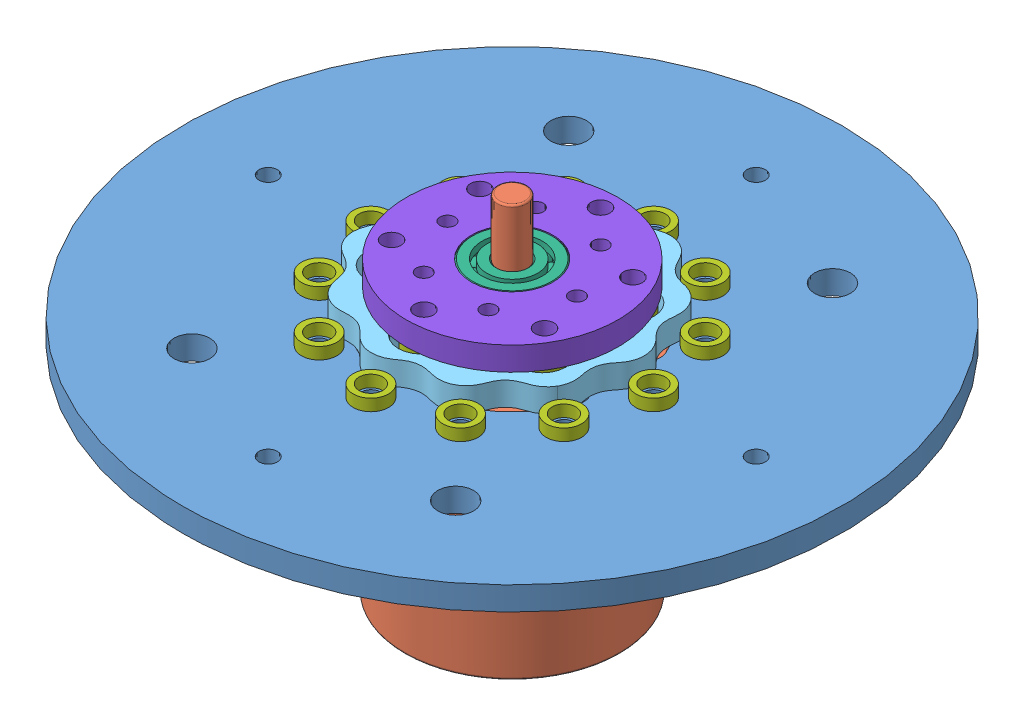
SolidWorks assembly Cycloidal Spindex Driver Assembly, configuration Default. Lengths in mm.
Overall size (177.8 93.26 177.8).
25 component instances, 8 part files, 20 mates.
Components (placement in the parent):
- Primary mounting-cooling plate-1: Primary mounting-cooling plate [Default] at (56.7267 81.535 113.5458) size (177.8 6.35 177.8)
- REV Neo Brushless-1: REV Neo Brushless [Default] at (56.7267 81.535 113.5458) x (1 0 0) z (0 1 0) size (60.81 60.02 93.26)
- Input from NEO-1: Input from NEO [Default] at (55.3519 87.885 112.7521) x (0.866043 0 0.49997) z (-0.49997 0 0.866043) size (12.7 6.35 12.7)
- 60355K505_Ball Bearing-1: 60355K505_Ball Bearing [60355K505] at (55.3519 91.06 112.7521) x (-0.255254 0 0.966874) z (0 -1 0) size (28.57 28.57 6.35)
- Cycloidal rotor-1: Cycloidal rotor [Default] at (55.3519 94.235 112.7521) x (-0.866026 0 -0.499999) z (0 -1 0) size (68.8 69.37 6.35)
- 5972K91_Ball Bearing-1: 5972K91_Ball Bearing [5972K91] at (56.7267 97.735 113.5458) x (-0.141937 0 0.989876) z (0 -1 0) size (22 22 7)
- Tiny bearing from thriftybot-2: Tiny bearing from thriftybot [Default] at (23.7311 87.885 94.4958) x (0.99755 0 -0.06995) z (0.06995 0 0.99755) size (9.53 3.17 9.53)
- Tiny bearing from thriftybot-3: Tiny bearing from thriftybot [Default] at (18.6267 87.885 113.5458) x (0.828929 0 -0.559354) z (0.559354 0 0.828929) size (9.53 3.17 9.53)
- Tiny bearing from thriftybot-4: Tiny bearing from thriftybot [Default] at (23.7311 87.885 132.5958) x (0.438196 0 -0.898879) z (0.898879 0 0.438196) size (9.53 3.17 9.53)
- Tiny bearing from thriftybot-5: Tiny bearing from thriftybot [Default] at (37.6767 87.885 146.5413) x (-0.06995 0 -0.99755) z (0.99755 0 -0.06995) size (9.53 3.17 9.53)
- Tiny bearing from thriftybot-6: Tiny bearing from thriftybot [Default] at (56.7267 87.885 151.6458) x (-0.559354 0 -0.828929) z (0.828929 0 -0.559354) size (9.53 3.17 9.53)
- Tiny bearing from thriftybot-7: Tiny bearing from thriftybot [Default] at (75.7767 87.885 146.5413) x (-0.898879 0 -0.438196) z (0.438196 0 -0.898879) size (9.53 3.17 9.53)
- Tiny bearing from thriftybot-8: Tiny bearing from thriftybot [Default] at (89.7223 87.885 132.5958) x (-0.99755 0 0.06995) z (-0.06995 0 -0.99755) size (9.53 3.17 9.53)
- Tiny bearing from thriftybot-9: Tiny bearing from thriftybot [Default] at (94.8267 87.885 113.5458) x (-0.828929 0 0.559354) z (-0.559354 0 -0.828929) size (9.53 3.17 9.53)
- Tiny bearing from thriftybot-10: Tiny bearing from thriftybot [Default] at (89.7223 87.885 94.4958) x (-0.438196 0 0.898879) z (-0.898879 0 -0.438196) size (9.53 3.17 9.53)
- Tiny bearing from thriftybot-11: Tiny bearing from thriftybot [Default] at (75.7767 87.885 80.5502) x (0.06995 0 0.99755) z (-0.99755 0 0.06995) size (9.53 3.17 9.53)
- Tiny bearing from thriftybot-12: Tiny bearing from thriftybot [Default] at (56.7267 87.885 75.4458) x (0.559354 0 0.828929) z (-0.828929 0 0.559354) size (9.53 3.17 9.53)
- Tiny bearing from thriftybot-13: Tiny bearing from thriftybot [Default] at (37.6767 87.885 80.5502) x (0.898879 0 0.438196) z (-0.438196 0 0.898879) size (9.53 3.17 9.53)
- Output disk-1: Output disk [Default] at (56.7267 94.885 113.5458) x (1 0 -0.000001) z (0.000001 0 1) size (57.15 6.35 57.15)
- Tiny bearing from thriftybot-14: Tiny bearing from thriftybot [Default] at (36.1045 91.71 125.452) x (0.999928 0 -0.011986) z (0.011986 0 0.999928) size (9.53 3.17 9.53)
- Tiny bearing from thriftybot-15: Tiny bearing from thriftybot [Default] at (56.7267 91.71 137.3583) x (0.489584 0 -0.871956) z (0.871956 0 0.489584) size (9.53 3.17 9.53)
- Tiny bearing from thriftybot-16: Tiny bearing from thriftybot [Default] at (77.349 91.71 125.452) x (-0.510345 0 -0.85997) z (0.85997 0 -0.510345) size (9.53 3.17 9.53)
- Tiny bearing from thriftybot-17: Tiny bearing from thriftybot [Default] at (77.3489 91.71 101.6395) x (-0.999928 0 0.011986) z (-0.011986 0 -0.999928) size (9.53 3.17 9.53)
- Tiny bearing from thriftybot-18: Tiny bearing from thriftybot [Default] at (56.7267 91.71 89.7333) x (-0.489584 0 0.871956) z (-0.871956 0 -0.489584) size (9.53 3.17 9.53)
- Tiny bearing from thriftybot-19: Tiny bearing from thriftybot [Default] at (36.1045 91.71 101.6395) x (0.510345 0 0.85997) z (-0.85997 0 0.510345) size (9.53 3.17 9.53)
Mates (geometry in assembly coordinates):
- Concentric6: concentric aligned: cylinder of Primary mounting-cooling plate-1 through (31.3267 87.885 113.5458) axis (0 1 0) radius 2.5527; cylinder of REV Neo Brushless-1 through (31.3267 81.535 113.5458) axis (0 1 0) radius 2.0193
- Concentric7: concentric anti-aligned: cylinder of Primary mounting-cooling plate-1 through (56.7267 81.535 113.5458) axis (0 1 0) radius 14.2875; cylinder of REV Neo Brushless-1 through (56.7267 85.035 113.5458) axis (0 -1 0) radius 9.525
- Coincident3: coincident anti-aligned: plane of Primary mounting-cooling plate-1 through (56.7267 81.535 113.5458) normal (0 -1 0); plane of REV Neo Brushless-1 through (56.7267 81.535 113.5458) normal (0 1 0)
- Concentric8: concentric anti-aligned: cylinder of REV Neo Brushless-1 through (56.7267 162.8487 113.5458) axis (0 -1 0) radius 4; cylinder of Input from NEO-1 through (56.7267 87.885 113.5458) axis (0 1 0) radius 4
- Coincident4: coincident aligned: plane of Primary mounting-cooling plate-1 through (56.7267 87.885 113.5458) normal (0 1 0); circle of Input from NEO-1
- Concentric9: concentric aligned: cylinder of Input from NEO-1 through (55.3519 94.235 112.7521) axis (0 -1 0) radius 6.35; cylinder of 60355K505_Ball Bearing-1 through (55.3519 87.885 112.7521) axis (0 -1 0) radius 6.35
- Coincident5: coincident aligned: plane of Input from NEO-1 through (55.3519 94.235 112.7521) normal (0 1 0); plane of 60355K505_Ball Bearing-1 through (48.9052 94.235 111.0501) normal (0 1 0)
- Concentric10: concentric aligned: cylinder of 60355K505_Ball Bearing-1 through (55.3519 87.885 112.7521) axis (0 -1 0) radius 14.2875; cylinder of Cycloidal rotor-1 through (55.3519 94.235 112.7521) axis (0 -1 0) radius 14.2875
- Coincident6: coincident aligned: plane of 60355K505_Ball Bearing-1 through (41.8446 94.235 109.1861) normal (0 1 0); plane of Cycloidal rotor-1 through (72.0902 94.235 83.6403) normal (0 1 0)
- Concentric11: concentric aligned: cylinder of REV Neo Brushless-1 through (56.7267 162.8487 113.5458) axis (0 -1 0) radius 4; cylinder of 5972K91_Ball Bearing-1 through (56.7267 94.235 113.5458) axis (0 -1 0) radius 4
- Coincident7: coincident anti-aligned: plane of Cycloidal rotor-1 through (72.0902 94.235 83.6403) normal (0 1 0); circle of 5972K91_Ball Bearing-1
- Concentric12: concentric aligned: circle of Primary mounting-cooling plate-1; circle of Tiny bearing from thriftybot-2
- Coincident8: coincident anti-aligned: plane of Primary mounting-cooling plate-1 through (56.7267 87.885 113.5458) normal (0 1 0); plane of Tiny bearing from thriftybot-2 through (23.7311 87.885 94.4958) normal (0 -1 0)
- Concentric13: concentric aligned: circle of Output disk-1; circle of Tiny bearing from thriftybot-14
- Coincident9: coincident anti-aligned: plane of Output disk-1 through (56.7267 94.885 113.5458) normal (0 -1 0); plane of Tiny bearing from thriftybot-14 through (36.1045 94.885 125.452) normal (0 1 0)
- Concentric14: concentric anti-aligned: cylinder of 5972K91_Ball Bearing-1 through (56.7267 94.235 113.5458) axis (0 -1 0) radius 11; cylinder of Output disk-1 through (56.7267 94.885 113.5458) axis (0 1 0) radius 11
- Coincident10: coincident aligned: plane of 5972K91_Ball Bearing-1 through (46.1845 101.235 112.0341) normal (0 1 0); plane of Output disk-1 through (56.7267 101.235 113.5458) normal (0 1 0)
- Tangent1: tangent: cylinder of assembly; face of Cycloidal rotor-1; cylinder of Tiny bearing from thriftybot-7 through (75.7767 91.06 146.5413) axis (0 -1 0) radius 4.7625
- Tangent4: tangent: cylinder of assembly; face of Cycloidal rotor-1; cylinder of Tiny bearing from thriftybot-8 through (89.7223 91.06 132.5958) axis (0 -1 0) radius 4.7625
- Tangent5: tangent aligned: cylinder of Cycloidal rotor-1 through (55.3518 94.235 88.9396) axis (0 -1 0) radius 6.35; cylinder of Tiny bearing from thriftybot-18 through (56.7267 94.885 89.7333) axis (0 -1 0) radius 4.7625
